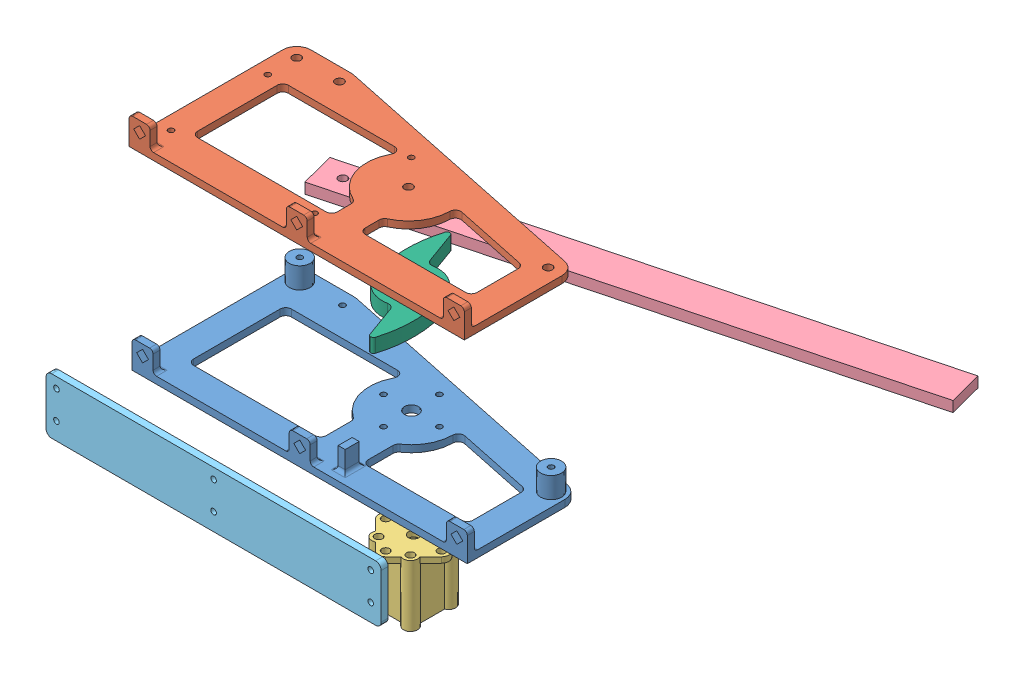
SolidWorks assembly R1_Expl, configuration Default. Lengths in mm.
Overall size (251.58 175.62 183.77).
6 component instances, 6 part files, 0 mates.
Components (placement in the parent):
- Motor_Plate-1: Motor_Plate [Default] at (68.2144 78.3241 104.509) size (152.4 12.7 76.2)
- Support_Plate-1: Support_Plate [Default] at (68.2144 167.0826 105.8617) size (152.4 12.7 76.2)
- Motor_Enclosure_B-1: Motor_Enclosure_B [Default] at (68.2144 32.1034 103.5085) x (-1 0 0) z (0 0 1) size (32 27.94 32)
- Mallet-1: Mallet [Default] at (11.0644 126.5883 78.514) x (0.967175 0 -0.254112) z (0.254112 0 0.967175) size (241.3 4.76 15.88)
- Base_Plate-1: Base_Plate [Default] at (69.4636 92.6894 195.7056) x (1 0 0) z (0 1 0) size (152.4 3.17 25.4)
- Cam_1-1: Cam_1 [Default] at (68.2144 124.9868 105.068) x (-0.33985 0 -0.94048) z (0 1 0) size (63.5 25.4 11.11)
